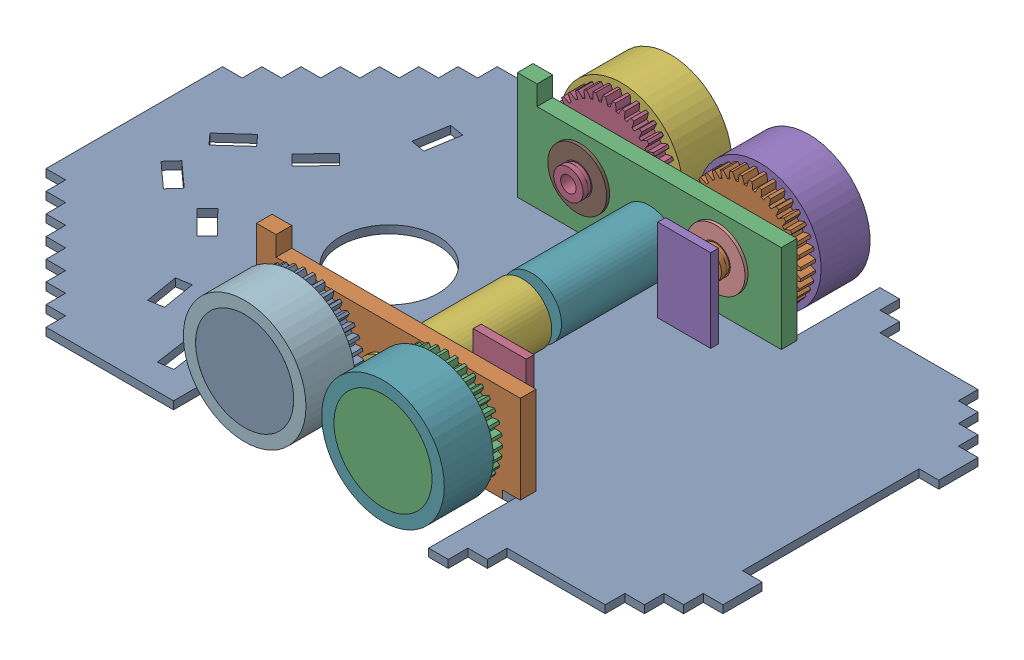
SolidWorks assembly uglyBob, configuration 기본. Lengths in mm.
Overall size (73 17.57 46).
21 component instances, 8 part files, 40 mates.
Components (placement in the parent):
- base-1: base [기본] at (-20.8248 -1.3791 0) size (73 0.8 46)
- motor_guard-1: motor_guard [기본] at (-20.8248 -1.8791 12.5) x (0 0 1) z (-1 0 0) size (1.6 11.8 26.9)
- motor_guard-2: motor_guard [기본] at (-20.8248 -1.8791 -14.1) x (0 0 1) z (-1 0 0) size (1.6 11.8 26.9)
- encoder-1: encoder [기본] at (-13.7748 -1.3791 9.8) x (0 0 -1) z (1 0 0) size (0.8 9.25 5.4)
- encoder-2: encoder [기본] at (-13.7748 -1.3791 -9.8) x (0 0 1) z (-1 0 0) size (0.8 9.25 5.4)
- motor-1: motor [기본] at (-20.8248 2.4209 14.4491) x (-0.984766 -0.173886 0) z (0 0 -1) size (6 6 18)
- motor-2: motor [기본] at (-20.8248 2.4209 -14.5396) x (0.973597 -0.228272 0) z (0 0 1) size (6 6 18)
- SE673ZZ-1: SE673ZZ [기본] at (-13.7748 4.3709 12.2) x (0.993482 0.113991 0) z (0 0 1) size (6 6 2.5)
- SE673ZZ-2: SE673ZZ [기본] at (-27.8748 4.3709 12.2) size (6 6 2.5)
- SE673ZZ-3: SE673ZZ [기본] at (-13.7748 4.3709 -14.7) x (0.999051 0.043544 0) z (0 0 1) size (6 6 2.5)
- SE673ZZ-4: SE673ZZ [기본] at (-27.8748 4.3709 -14.7) x (0.999006 0.044566 0) z (0 0 1) size (6 6 2.5)
- dNaNo Tire-1: dNaNo Tire [기본] at (-27.8748 4.3709 21.7) x (0 0 -1) z (-0.432677 0.901549 0) size (5 12.5 12.5)
- wheel-1: wheel [기본] at (-27.8748 4.3709 16.7) x (0.997118 0.075865 0) z (0 0 1) size (11.4 11.4 10.4)
- wheel-2: wheel [기본] at (-13.7748 4.3709 -16.7) x (0.995229 -0.097568 0) z (0 0 -1) size (11.4 11.4 10.4)
- wheel-3: wheel [기본] at (-13.7748 4.3709 16.7) size (11.4 11.4 10.4)
- wheel-4: wheel [기본] at (-27.8748 4.3709 -16.7) x (0.923728 0.383049 0) z (0 0 -1) size (11.4 11.4 10.4)
- dNaNo Tire-2: dNaNo Tire [기본] at (-13.7748 4.3709 -21.7) x (0 0 1) z (0.995709 -0.09254 0) size (5 12.5 12.5)
- dNaNo Tire-3: dNaNo Tire [기본] at (-27.8748 4.3709 -21.7) x (0 0 1) z (-0.993395 -0.114746 0) size (5 12.5 12.5)
- dNaNo Tire-4: dNaNo Tire [기본] at (-13.7748 4.3709 21.7) x (0 0 -1) z (0.781163 0.624327 0) size (5 12.5 12.5)
- pinion-1: pinion [기본] at (-20.8248 2.4209 -16.2274) x (0.994752 0.102315 0) z (0 0 1) size (4.2 4.2 1.5)
- pinion-2: pinion [기본] at (-20.8248 2.4209 14.5575) x (0.984813 0.173619 0) z (0 0 1) size (4.2 4.2 1.5)
Mates (geometry in assembly coordinates):
- 일치1: coincident: plane of base-1 through (-20.8248 -0.5791 0) normal (0 1 0); line of motor_guard-1 through (-13.7748 -0.5791 14.1) axis (-1 0 0)
- 일치2: coincident anti-aligned: plane of base-1 through (-32.4748 -0.5791 12.5) normal (0 0 1); plane of motor_guard-1 through (-20.8248 2.4209 12.5) normal (0 0 -1)
- 일치3: coincident anti-aligned: plane of base-1 through (-32.4748 -0.5791 14.1) normal (1 0 0); plane of motor_guard-1 through (-32.4748 -0.5791 14.1) normal (-1 0 0)
- 일치4: coincident: plane of base-1 through (-20.8248 -0.5791 0) normal (0 1 0); line of motor_guard-2 through (-27.8748 -0.5791 -14.1) axis (1 0 0)
- 일치5: coincident anti-aligned: plane of base-1 through (-9.1748 -0.5791 -12.5) normal (0 0 -1); plane of motor_guard-2 through (-20.8248 2.4209 -12.5) normal (0 0 1)
- 일치6: coincident anti-aligned: plane of base-1 through (-9.1748 -0.5791 -14.1) normal (-1 0 0); plane of motor_guard-2 through (-9.1748 -0.5791 -12.5) normal (1 0 0)
- 일치7: coincident anti-aligned: plane of base-1 through (-16.2748 -0.5791 9) normal (0 0 1); plane of encoder-1 through (-13.7748 -1.3791 9) normal (0 0 -1)
- 일치8: coincident anti-aligned: plane of base-1 through (-16.2748 -0.5791 -9) normal (0 0 -1); plane of encoder-2 through (-13.7748 -1.3791 -9) normal (0 0 1)
- 일치9: coincident anti-aligned: plane of base-1 through (-11.2748 -0.5791 -9.85) normal (-1 0 0); plane of encoder-2 through (-11.2748 -1.3791 -9) normal (1 0 0)
- 일치10: coincident anti-aligned: plane of base-1 through (-11.2748 -0.5791 9.85) normal (-1 0 0); plane of encoder-1 through (-11.2748 -1.3791 9) normal (1 0 0)
- 일치11: coincident: plane of base-1 through (-20.8248 -0.5791 0) normal (0 1 0); line of encoder-1 through (-11.2748 -0.5791 9) axis (0 0 1)
- 일치12: coincident anti-aligned: plane of base-1 through (-20.8248 -0.5791 0) normal (0 1 0); plane of encoder-2 through (-11.2748 -0.5791 -9) normal (0 -1 0)
- 동심1: concentric aligned: cylinder of motor_guard-2 through (-20.8248 2.4209 -12.5) axis (0 0 -1) radius 3; cylinder of motor-2 through (-20.8248 2.4209 -0.5396) axis (0 0 -1) radius 3
- 일치13: coincident anti-aligned: circle of motor_guard-1; cylinder of motor-1 through (-20.8248 2.4209 0.4491) axis (0 0 1) radius 3
- 동심2: concentric aligned: cylinder of motor_guard-2 through (-27.8748 4.3709 -12.5) axis (0 0 -1) radius 3; cylinder of SE673ZZ-4 through (-27.8748 4.3709 -12.2) axis (0 0 -1) radius 3
- 동심3: concentric aligned: cylinder of motor_guard-2 through (-13.7748 4.3709 -12.5) axis (0 0 -1) radius 3; cylinder of SE673ZZ-3 through (-13.7748 4.3709 -12.2) axis (0 0 -1) radius 3
- 동심4: concentric aligned: cylinder of motor_guard-1 through (-13.7748 4.3709 14.1) axis (0 0 -1) radius 3; cylinder of SE673ZZ-1 through (-13.7748 4.3709 14.7) axis (0 0 -1) radius 3
- 동심5: concentric aligned: cylinder of motor_guard-1 through (-27.8748 4.3709 14.1) axis (0 0 -1) radius 3; cylinder of SE673ZZ-2 through (-27.8748 4.3709 14.7) axis (0 0 -1) radius 3
- 동심6: concentric anti-aligned: cylinder of SE673ZZ-2 through (-27.8748 4.3709 14.7) axis (0 0 -1) radius 1.5; cylinder of wheel-1 through (-27.8748 4.3709 11.3) axis (0 0 1) radius 1.5
- 일치14: coincident anti-aligned: plane of SE673ZZ-2 through (-27.8748 4.3709 14.7) normal (0 0 1); plane of wheel-1 through (-27.8748 4.3709 14.7) normal (0 0 -1)
- 동심7: concentric anti-aligned: cylinder of dNaNo Tire-1 through (-27.8748 4.3709 16.7) axis (0 0 1) radius 5; cylinder of wheel-1 through (-27.8748 4.3709 21.7) axis (0 0 -1) radius 5
- 일치16: coincident anti-aligned: circle of dNaNo Tire-1; plane of wheel-1 through (-27.0241 6.8593 16.7) normal (0 0 1)
- 동심8: concentric anti-aligned: cylinder of wheel-3 through (-13.7748 4.3709 21.7) axis (0 0 -1) radius 5; cylinder of dNaNo Tire-4 through (-13.7748 4.3709 16.7) axis (0 0 1) radius 5
- 동심9: concentric anti-aligned: cylinder of wheel-4 through (-27.8748 4.3709 -21.7) axis (0 0 1) radius 5; cylinder of dNaNo Tire-3 through (-27.8748 4.3709 -16.7) axis (0 0 -1) radius 5
- 동심10: concentric anti-aligned: cylinder of wheel-2 through (-13.7748 4.3709 -21.7) axis (0 0 1) radius 5; cylinder of dNaNo Tire-2 through (-13.7748 4.3709 -16.7) axis (0 0 -1) radius 5
- 일치17: coincident aligned: plane of wheel-2 through (-13.7748 4.3709 -21.7) normal (0 0 -1); plane of dNaNo Tire-2 through (-13.7748 4.3709 -21.7) normal (0 0 -1)
- 일치18: coincident anti-aligned: plane of wheel-4 through (-27.8748 4.3709 -21.7) normal (0 0 -1); circle of dNaNo Tire-3
- 일치19: coincident aligned: plane of wheel-3 through (-13.7748 4.3709 21.7) normal (0 0 1); plane of dNaNo Tire-4 through (-13.7748 4.3709 21.7) normal (0 0 1)
- 동심11: concentric anti-aligned: cylinder of SE673ZZ-1 through (-13.7748 4.3709 14.7) axis (0 0 -1) radius 1.5; cylinder of wheel-3 through (-13.7748 4.3709 11.3) axis (0 0 1) radius 1.5
- 일치20: coincident anti-aligned: plane of SE673ZZ-1 through (-13.7748 4.3709 14.7) normal (0 0 1); plane of wheel-3 through (-13.7748 4.3709 14.7) normal (0 0 -1)
- 동심12: concentric aligned: cylinder of SE673ZZ-4 through (-27.8748 4.3709 -12.2) axis (0 0 -1) radius 1.5; cylinder of wheel-4 through (-27.8748 4.3709 -11.3) axis (0 0 -1) radius 1.5
- 일치21: coincident anti-aligned: plane of SE673ZZ-4 through (-27.8748 4.3709 -14.7) normal (0 0 -1); plane of wheel-4 through (-27.8748 4.3709 -14.7) normal (0 0 1)
- 동심13: concentric aligned: cylinder of SE673ZZ-3 through (-13.7748 4.3709 -12.2) axis (0 0 -1) radius 1.5; cylinder of wheel-2 through (-13.7748 4.3709 -11.3) axis (0 0 -1) radius 1.5
- 일치22: coincident anti-aligned: plane of SE673ZZ-3 through (-13.7748 4.3709 -14.7) normal (0 0 -1); plane of wheel-2 through (-13.7748 4.3709 -14.7) normal (0 0 1)
- 거리1: distance = 0.6 mm: plane of SE673ZZ-3 through (-13.7748 4.3709 -14.7) normal (0 0 -1); line of motor_guard-2 through (-32.2748 8.4209 -14.1) axis (1 0 0)
- 일치24: coincident aligned: plane of wheel-2 through (-13.7748 4.3709 -21.7) normal (0 0 -1); plane of wheel-4 through (-27.8748 4.3709 -21.7) normal (0 0 -1)
- 거리2: distance = 0.6 mm aligned: plane of SE673ZZ-1 through (-13.7748 4.3709 14.7) normal (0 0 1); plane of motor_guard-1 through (-20.8248 2.4209 14.1) normal (0 0 1)
- 일치26: coincident aligned: plane of dNaNo Tire-1 through (-27.8748 4.3709 21.7) normal (0 0 1); plane of dNaNo Tire-4 through (-13.7748 4.3709 21.7) normal (0 0 1)
- 동심14: concentric aligned: cylinder of motor-1 through (-20.8248 2.4209 18.4491) axis (0 0 -1) radius 0.4; cylinder of pinion-2 through (-20.8248 2.4209 16.0575) axis (0 0 -1) radius 0.35
- 동심15: concentric anti-aligned: cylinder of motor-2 through (-20.8248 2.4209 -18.5396) axis (0 0 1) radius 0.4; cylinder of pinion-1 through (-20.8248 2.4209 -14.7274) axis (0 0 -1) radius 0.35
